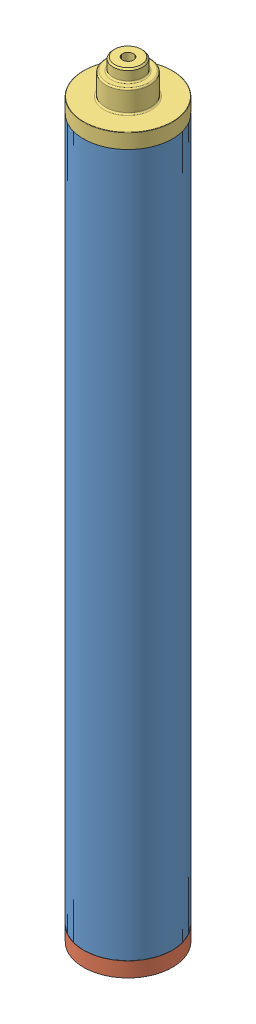
SolidWorks assembly CompMotorMount29in, configuration Default. Lengths in mm.
Overall size (105.47 657.1 105.47).
3 component instances, 3 part files, 4 mates.
Components (placement in the parent):
- MotorMount-1: MotorMount [Default] at (-54.5297 -352.2585 17.5311) size (76.2 602.49 76.2)
- MotorRetainerAft-1: MotorRetainerAft [Default] at (-54.5297 -352.2585 17.5311) x (-0.837169 0 -0.546944) z (-0.546944 0 0.837169) size (76.2 38.1 76.2)
- MotorRetainerFore-1: MotorRetainerFore [Default] at (-54.5297 224.8295 17.5311) x (0.936036 0 0.351904) z (-0.351904 0 0.936036) size (76.2 67.31 76.2)
Mates (geometry in assembly coordinates):
- Concentric1: concentric aligned: cylinder of MotorMount-1 through (-54.5297 250.2295 17.5311) axis (0 -1 0) radius 37.465; cylinder of MotorRetainerFore-1 through (-54.5297 250.2295 17.5311) axis (0 -1 0) radius 37.465
- Coincident1: coincident anti-aligned: plane of MotorMount-1 through (-54.5297 250.2295 17.5311) normal (0 1 0); plane of MotorRetainerFore-1 through (-54.5297 250.2295 17.5311) normal (0 -1 0)
- Coincident2: coincident anti-aligned: plane of MotorMount-1 through (-54.5297 -352.2585 17.5311) normal (0 -1 0); plane of MotorRetainerAft-1 through (-54.5297 -352.2585 17.5311) normal (0 1 0)
- Concentric2: concentric aligned: circle of MotorMount-1; circle of MotorRetainerAft-1
